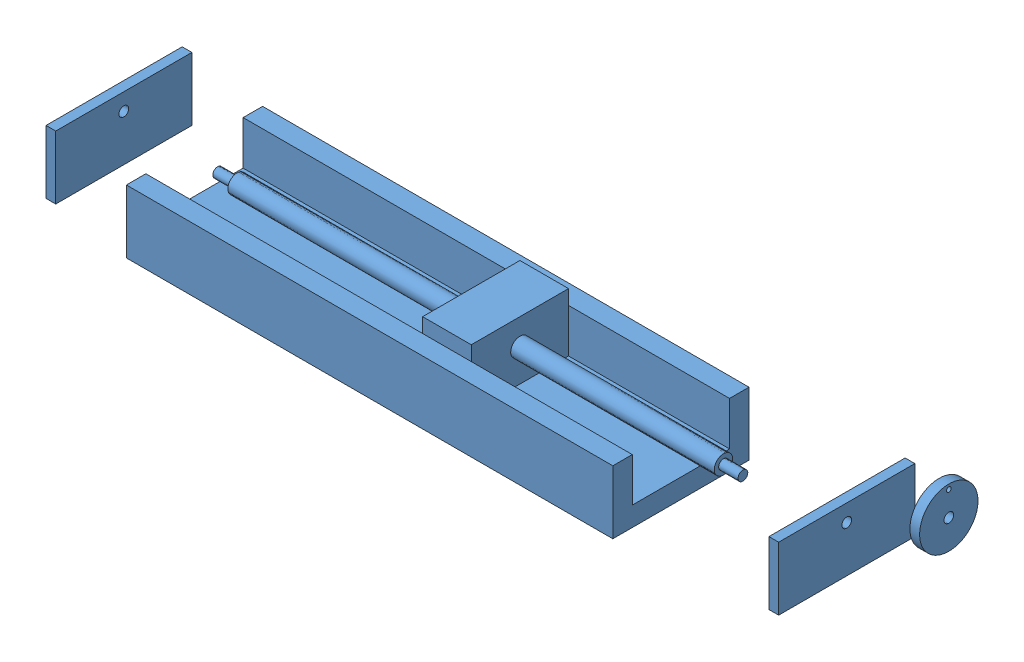
SolidWorks assembly Ensamble_mesa, configuration Default. Lengths in mm.
Overall size (636.11 221.58 321.92).
6 component instances, 1 part files, 3 mates.
Components (placement in the parent):
- Mesa_Lineal-1: Mesa_Lineal [Base_Lineal] at (-30.058 234.0202 376.006) size (500 65 140)
- Mesa_Lineal-2: Mesa_Lineal [Tapa_Lineal] at (515.9124 149.2416 261.5032) size (10 65 140)
- Mesa_Lineal-3: Mesa_Lineal [Tapa_Lineal] at (-65.0722 305.8238 423.6341) size (10 65 140)
- Mesa_Lineal-4: Mesa_Lineal [Carro_lineal] at (254.4408 264.0202 376.006) size (50 60 100)
- Mesa_Lineal-5: Mesa_Lineal [Husillo] at (263.6876 267.1829 376.006) x (1 0 0) z (0 -0.932506 -0.361156) size (540 19 19)
- Mesa_Lineal-6: Mesa_Lineal [Default] at (561.0332 161.2462 201.7123) size (10 60 60)
Mates (geometry in assembly coordinates):
- Coincidente1: coincident anti-aligned: plane of Mesa_Lineal-1 through (469.942 234.0202 326.006) normal (0 1 0); plane of Mesa_Lineal-4 through (304.4408 234.0202 326.006) normal (0 -1 0)
- Coincidente2: coincident anti-aligned: plane of Mesa_Lineal-1 through (469.942 234.0202 426.006) normal (0 0 -1); plane of Mesa_Lineal-4 through (304.4408 234.0202 426.006) normal (0 0 1)
- Concéntrica4: concentric aligned: circle of Mesa_Lineal-4; circle of Mesa_Lineal-5
